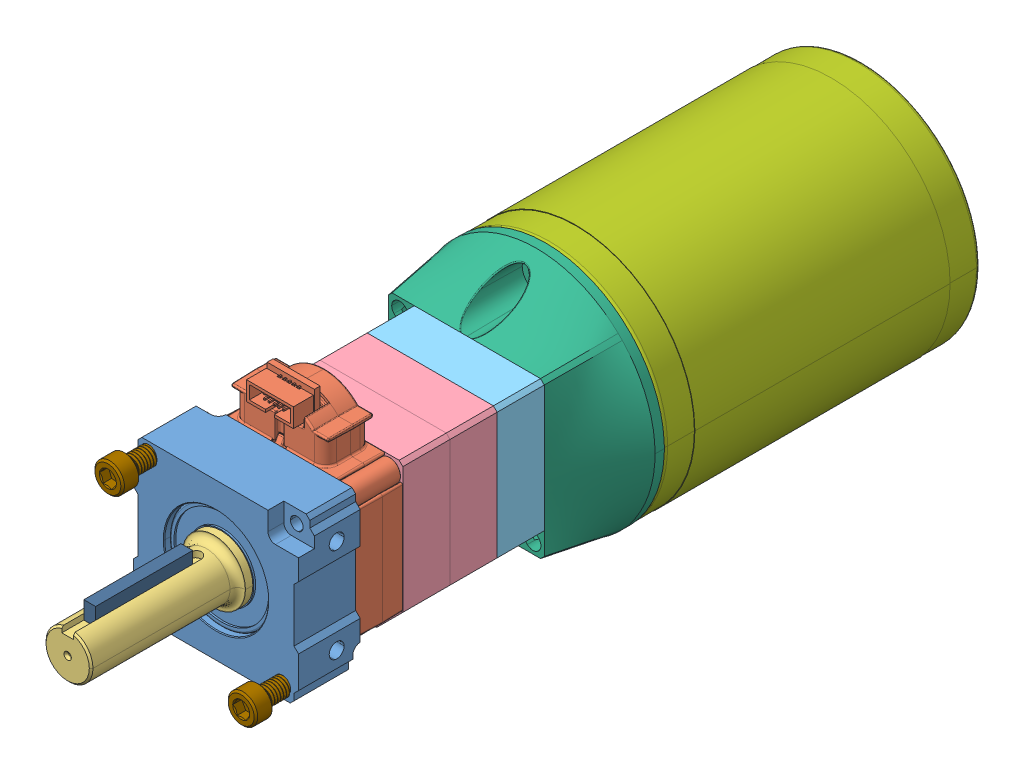
SolidWorks assembly A12220110_FRONT_SHAFT_ASSEMBLY, configuration Default. Lengths in mm.
Overall size (64.01 67.32 307.03).
17 component instances, 11 part files, 7 mates.
Components (placement in the parent):
- A12220105_MOTOR_BRACKET_ASSEMBLY-1: A12220105_MOTOR_BRACKET_ASSEMBLY [Default] at origin size (64.01 67.32 280.24) (flexible)
  - 12220106-051 MiniCIM Motor Assembly-1: 12220106-051 MiniCIM Motor Assembly [Default] at origin size (64.01 67.32 218.97)
    - Gearbox Assembly-1: Gearbox Assembly [Default] at (34.0244 -12.4567 -92.7758) x (0 0 1) z (-1 0 0) size (123.35 56.32 44.45)
      - Output Housing-2: Output Housing [Default] at (64.8023 -0.856 18.2213) x (1 0 0) z (0 -1 0) size (75.7 44.45 56.32)
        - Housing-1: Housing [Default] at (19.8785 -6.4219 -11.5232) size (18.13 44.45 42)
        - Encoder.step-1: Encoder.step [Default] at (12.6785 15.8031 -11.5232) x (0 0 1) z (-1 0 0) size (56.32 42 21.21)
        - Gearbox_output_shaft-1: Gearbox_output_shaft [Default] at origin size (63.51 17 17)
      - Ring Gears-1: Ring Gears [Default] at (71.9808 10.6671 11.7994) x (1 0 0) z (0 -1 0) size (32.2 42 42)
      - Ring Gear Stage 3-1: Ring Gear Stage 3 [Default] at (59.2808 10.6671 11.7994) x (1 0 0) z (0 -1 0) size (28.65 42 42)
    - CIM Adaptor.step-1: CIM Adaptor.step [Default] at (0 -1.7896 -68.72) x (0 -1 0) z (-1 0 0) size (64.01 21.63 64.01)
    - Mini CIM-1: Mini CIM [Default] at (0 -1.7896 -80.245) x (0 0 -1) z (1 0 0) size (101.22 64.01 64.01)
    - 8-32 X 3IN LG - Black-Oxide Alloy Steel Socket Head Screw (90044A516)-1: 8-32 X 3IN LG - Black-Oxide Alloy Steel Socket Head Screw (90044A516) [90044A516] at (17.5 15.7104 -75.245) x (-0.08536 0.99635 0) z (0 0 -1) size (6.86 6.86 81.33)
    - 8-32 X 3IN LG - Black-Oxide Alloy Steel Socket Head Screw (90044A516)-3: 8-32 X 3IN LG - Black-Oxide Alloy Steel Socket Head Screw (90044A516) [90044A516] at (-17.5 -19.2896 -75.245) x (-0.242255 0.970213 0) z (0 0 -1) size (6.86 6.86 81.33)
  - 10-32 X 0.875IN LG - Black-Oxide Alloy Steel Socket Head Screw (91251A346)-1: 10-32 X 0.875IN LG - Black-Oxide Alloy Steel Socket Head Screw (91251A346) [91251A346] at (-17.9605 16.1709 6.1805) x (0.130335 0.99147 0) z (0 0 1) size (7.94 7.94 27.67)
  - 10-32 X 0.875IN LG - Black-Oxide Alloy Steel Socket Head Screw (91251A346)-2: 10-32 X 0.875IN LG - Black-Oxide Alloy Steel Socket Head Screw (91251A346) [91251A346] at (17.9605 -19.7501 6.1805) x (0.872398 0.488796 0) z (0 0 1) size (7.94 7.94 27.67)
- PB2023-M005 ROTARY SHAFT-1: PB2023-M005 ROTARY SHAFT [Default] at (0 -1.7896 136.57) x (0 0 -1) z (1 0 0) size (126.56 25 25)
- 12220110_MOTOR_KEY-1: 12220110_MOTOR_KEY [Default] at (0 5.1764 16.3975) size (3.17 4.76 26.16)
Mates (geometry in assembly coordinates):
- Coincident1: coordinate: point of A12220105_MOTOR_BRACKET_ASSEMBLY-1
- Concentric1: concentric anti-aligned: cylinder of A12220105_MOTOR_BRACKET_ASSEMBLY-1/MiniCIM Motor Assembly-1/Gearbox Assembly-1/Output Housing-2/Gearbox_output_shaft-1 through (0 -1.7896 48.5052) axis (0 0 -1) radius 6.335; cylinder of 12220102_SHAFT-1 through (0 -1.7896 145.711) axis (0 0 1) radius 10
- Coincident3: coincident anti-aligned: plane of A12220105_MOTOR_BRACKET_ASSEMBLY-1/MiniCIM Motor Assembly-1/Gearbox Assembly-1/Output Housing-2/Gearbox_output_shaft-1 through (0 2.7951 14.1052) normal (0 1 0); plane of 12220110_MOTOR_KEY-1 through (-1.5875 2.7951 42.5595) normal (0 -1 0)
- Symmetric1: symmetric aligned: plane of A12220105_MOTOR_BRACKET_ASSEMBLY-1/MiniCIM Motor Assembly-1/Gearbox Assembly-1/Output Housing-2/Gearbox_output_shaft-1 through (-1.5875 2.7951 14.1052) normal (1 0 0); plane of A12220105_MOTOR_BRACKET_ASSEMBLY-1/MiniCIM Motor Assembly-1/Gearbox Assembly-1/Output Housing-2/Gearbox_output_shaft-1 through (1.5875 2.7951 14.1052) normal (-1 0 0); plane of 12220110_MOTOR_KEY-1 through (0 5.1764 16.3975) normal (1 0 0)
- Distance1: distance = 1.48 mm anti-aligned: plane of 12220102_SHAFT-1 through (0 10.7104 10.01) normal (0 0 -1); plane of A12220105_MOTOR_BRACKET_ASSEMBLY-1/MiniCIM Motor Assembly-1/Gearbox Assembly-1/Output Housing-2/Housing-1 through (-22.225 -24.0146 8.53) normal (0 0 1)
- Coincident7: coincident aligned: plane of A12220105_MOTOR_BRACKET_ASSEMBLY-1/MiniCIM Motor Assembly-1/Gearbox Assembly-1/Output Housing-2/Gearbox_output_shaft-1 through (-1.5875 2.7951 14.1052) normal (1 0 0); plane of 12220102_SHAFT-1 through (-1.5875 -14.2906 136.57) normal (1 0 0)
- Coincident8: coincident anti-aligned: line of 12220102_SHAFT-1 through (-1.5875 4.3588 16.3975) axis (0 1 0); line of 12220110_MOTOR_KEY-1 through (-1.5875 7.5576 16.3975) axis (0 -1 0)
